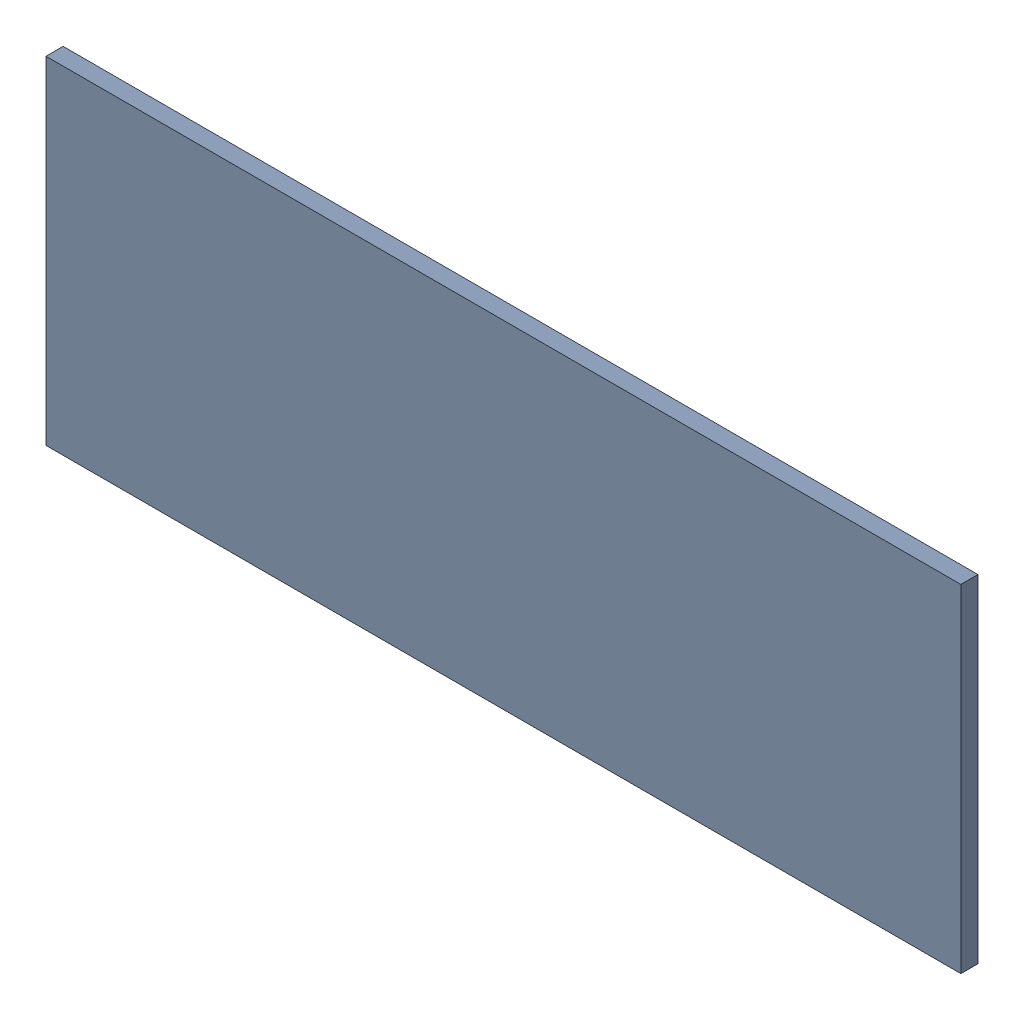
SolidWorks assembly Pad RAK4600-12(14.5mm,13.75mm) on Top Layer, configuration Predeterminado. Lengths in mm.
Overall size (1.9 0.7 0.04).
2 component instances, 1 part files, 0 mates.
Components (placement in the parent):
- Pad RAK4600-12(14.5mm,13.75mm) on Top Layer-1-1: Pad RAK4600-12(14.5mm,13.75mm) on Top Layer-1 [Predeterminado] at (-68.317 -44.187 -0.0457) size (1.9 0.7 0.04)
  - Pad RAK4600-12(14.5mm,13.75mm) on Top Layer-Part-1-1: Pad RAK4600-12(14.5mm,13.75mm) on Top Layer-Part-1 [Predeterminado] at origin size (1.9 0.7 0.04)
